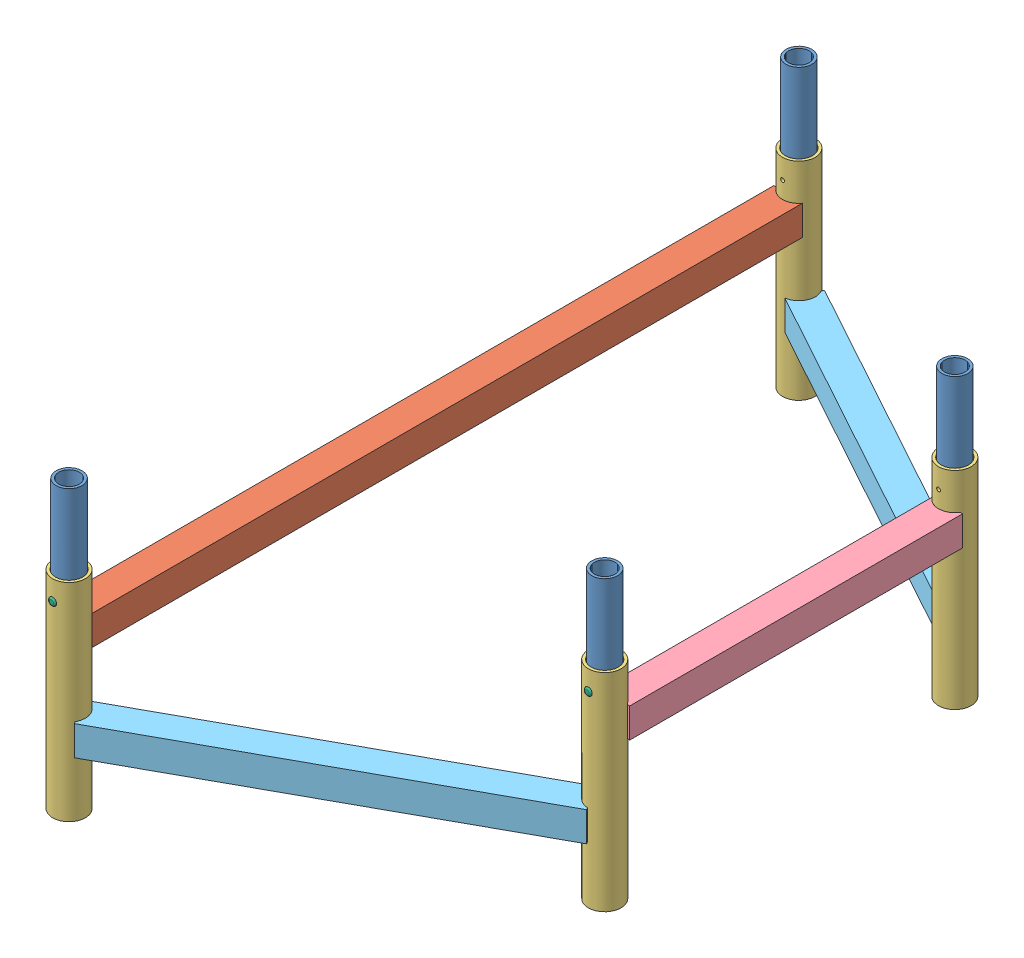
SolidWorks assembly GE-19019, configuration Default. Lengths in mm.
Overall size (487.47 368.3 985.16).
17 component instances, 6 part files, 16 mates.
Components (placement in the parent):
- GE-19018-1: GE-19018 [Default] at (21.082 -16.51 469.9) size (33.4 203.2 33.4)
- GE-19018-2: GE-19018 [Default] at (466.3864 -16.51 -225.425) x (-1 0 0) z (0 0 -1) size (33.4 203.2 33.4)
- GE-19018-3: GE-19018 [Default] at (466.3864 -16.51 225.425) size (33.4 203.2 33.4)
- GE-19018-4: GE-19018 [Default] at (21.082 -16.51 -469.9) size (33.4 203.2 33.4)
- GE-19016-1: GE-19016 [Default] at origin size (487.47 266.7 981.96)
  - GE-19016-03-1: GE-19016-03 [Default] at origin size (38.1 38.1 917.58)
  - GE-19016-04-1: GE-19016-04 [Default] at (21.082 -181.61 -469.9) size (42.16 266.7 42.16)
  - GE-19016-04-2: GE-19016-04 [Default] at (21.082 -181.61 469.9) size (42.16 266.7 42.16)
  - GE-19016-04-3: GE-19016-04 [Default] at (466.3864 -181.61 225.425) size (42.16 266.7 42.16)
  - GE-19016-04-4: GE-19016-04 [Default] at (466.3864 -181.61 -225.425) size (42.16 266.7 42.16)
  - GE-19016-01-1: GE-19016-01 [Default] at (487.4684 0 0) x (-1 0 0) z (0 0 -1) size (38.1 38.1 428.62)
  - GE-19016-02-1: GE-19016-02 [Default] at (253.8799 -108.585 -366.1426) x (-0.48125 0 0.876583) z (-0.876583 0 -0.48125) size (38.1 38.1 485.78)
  - GE-19016-02-2: GE-19016-02 [Default] at (253.8799 -108.585 366.1426) x (-0.48125 0 -0.876583) z (0.876583 0 -0.48125) size (38.1 38.1 485.78)
- rivet_.1875_.251-.375-1: rivet_.1875_.251-.375 [Default] at (466.3864 59.69 246.507) size (10.01 10.01 16.21)
- rivet_.1875_.251-.375-2: rivet_.1875_.251-.375 [Default] at (21.082 59.69 490.982) size (10.01 10.01 16.21)
- rivet_.1875_.251-.375-3: rivet_.1875_.251-.375 [Default] at (21.082 59.69 -490.982) x (-1 0 0) z (0 0 -1) size (10.01 10.01 16.21)
- rivet_.1875_.251-.375-4: rivet_.1875_.251-.375 [Default] at (466.3864 59.69 -246.507) x (-0.923728 -0.383049 0) z (0 0 -1) size (10.01 10.01 16.21)
Mates (geometry in assembly coordinates):
- Concentric17: concentric: cylinder of GE-19018-4 through (21.082 59.69 -453.1995) axis (0 0 1) radius 2.4574; cylinder of GE-19016-1/GE-19016-04-1 through (21.082 59.69 -448.818) axis (0 0 1) radius 2.4574
- Concentric18: concentric: cylinder of assembly; cylinder of assembly; cylinder of GE-19018-3 through (466.3864 59.69 242.1255) axis (0 0 1) radius 2.4574; cylinder of GE-19016-1/GE-19016-04-3 through (466.3864 59.69 246.507) axis (0 0 1) radius 2.4574
- Concentric19: concentric: cylinder of assembly; cylinder of assembly; cylinder of GE-19018-2 through (466.3864 59.69 -242.1255) axis (0 0 -1) radius 2.4574; cylinder of GE-19016-1/GE-19016-04-4 through (466.3864 59.69 -204.343) axis (0 0 1) radius 2.4574
- Concentric20: concentric: cylinder of GE-19018-1 through (21.082 59.69 486.6005) axis (0 0 1) radius 2.4574; cylinder of GE-19016-1/GE-19016-04-2 through (21.082 59.69 490.982) axis (0 0 1) radius 2.4574
- Concentric21: concentric: cylinder of GE-19018-1 through (21.082 186.69 469.9) axis (0 -1 0) radius 16.7005; cylinder of GE-19016-1/GE-19016-04-2 through (21.082 85.09 469.9) axis (0 -1 0) radius 17.526
- Concentric22: concentric: cylinder of assembly; cylinder of assembly; cylinder of GE-19018-3 through (466.3864 186.69 225.425) axis (0 -1 0) radius 16.7005; cylinder of GE-19016-1/GE-19016-04-3 through (466.3864 85.09 225.425) axis (0 -1 0) radius 17.526
- Concentric23: concentric: cylinder of assembly; cylinder of assembly; cylinder of GE-19018-2 through (466.3864 186.69 -225.425) axis (0 -1 0) radius 16.7005; cylinder of GE-19016-1/GE-19016-04-4 through (466.3864 85.09 -225.425) axis (0 -1 0) radius 17.526
- Concentric24: concentric: cylinder of GE-19018-4 through (21.082 186.69 -469.9) axis (0 -1 0) radius 16.7005; cylinder of GE-19016-1/GE-19016-04-1 through (21.082 85.09 -469.9) axis (0 -1 0) radius 17.526
- Concentric25: concentric: cylinder of assembly; cylinder of assembly; cylinder of GE-19016-1/GE-19016-04-3 through (466.3864 59.69 246.507) axis (0 0 1) radius 2.4574; cylinder of rivet_.1875_.251-.375-1 through (466.3864 59.69 231.902) axis (0 0 1) radius 2.3813
- Tangent2: tangent: cylinder of assembly; plane of assembly; cylinder of GE-19016-1/GE-19016-04-3 through (466.3864 85.09 225.425) axis (0 -1 0) radius 21.082; plane of rivet_.1875_.251-.375-1 through (466.3864 59.69 246.507) normal (0 0 -1)
- Concentric26: concentric: cylinder of assembly; cylinder of assembly; cylinder of GE-19016-1/GE-19016-04-2 through (21.082 59.69 490.982) axis (0 0 1) radius 2.4574; cylinder of rivet_.1875_.251-.375-2 through (21.082 59.69 476.377) axis (0 0 1) radius 2.3813
- Tangent3: tangent: cylinder of assembly; plane of assembly; cylinder of GE-19016-1/GE-19016-04-2 through (21.082 85.09 469.9) axis (0 -1 0) radius 21.082; plane of rivet_.1875_.251-.375-2 through (21.082 59.69 490.982) normal (0 0 -1)
- Concentric27: concentric: cylinder of assembly; cylinder of assembly; cylinder of GE-19016-1/GE-19016-04-4 through (466.3864 59.69 -204.343) axis (0 0 1) radius 2.4574; cylinder of rivet_.1875_.251-.375-4 through (466.3864 59.69 -231.902) axis (0 0 -1) radius 2.3813
- Tangent4: tangent: cylinder of assembly; plane of assembly; cylinder of GE-19016-1/GE-19016-04-4 through (466.3864 85.09 -225.425) axis (0 -1 0) radius 21.082; plane of rivet_.1875_.251-.375-4 through (466.3864 59.69 -246.507) normal (0 0 1)
- Concentric28: concentric: cylinder of GE-19016-1/GE-19016-04-1 through (21.082 59.69 -448.818) axis (0 0 1) radius 2.4574; cylinder of rivet_.1875_.251-.375-3 through (21.082 59.69 -476.377) axis (0 0 -1) radius 2.3813
- Tangent5: tangent: cylinder of GE-19016-1/GE-19016-04-1 through (21.082 85.09 -469.9) axis (0 -1 0) radius 21.082; plane of rivet_.1875_.251-.375-3 through (21.082 59.69 -490.982) normal (0 0 1)
